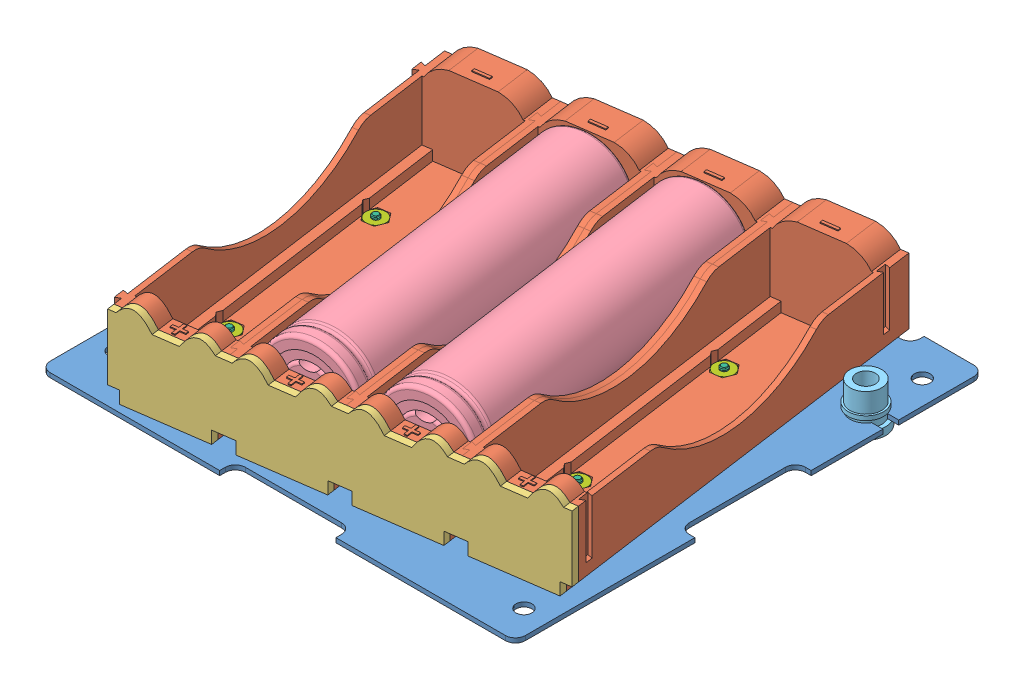
SolidWorks assembly M101 Battery Assembly, configuration Default. Lengths in mm.
Overall size (95.95 22.45 94.09).
43 component instances, 8 part files, 90 mates.
Components (placement in the parent):
- M103 Battery Plate-1: M103 Battery Plate [Default] at (-64.3857 -9.2767 40.2779) size (95.46 0.9 94.09)
- M102 Battery Holder Assembly-1: M102 Battery Holder Assembly [Default] at (-18.4887 8.3398 -10.8914) x (-0.990268 0 0.139173) z (-0.139173 0 -0.990268) size (83.6 18.9 79.5)
  - single battery holder-1: single battery holder [Default] at (-25.8788 -16.7165 25.0128) size (21.65 18.9 78)
  - single battery holder-2: single battery holder [Default] at (-5.2288 -16.7165 25.0128) size (21.65 18.9 78)
  - single battery holder-3: single battery holder [Default] at (15.4212 -16.7165 25.0128) size (21.65 18.9 78)
  - single battery holder-4: single battery holder [Default] at (36.0712 -16.7165 25.0128) size (21.65 18.9 78)
  - battery pack cap-1: battery pack cap [Default] at (36.0712 -16.7165 -52.9872) x (-1 0 0) z (0 0 -1) size (82.6 17.7 1.5)
- Battery, 18650_LGABC11865_3.7V-2: Battery, 18650_LGABC11865_3.7V [Default] at (-11.1122 2.4733 4.0244) x (-0.990268 0 0.139173) z (0 1 0) size (18.3 64.95 18.3)
- Battery, 18650_LGABC11865_3.7V-3: Battery, 18650_LGABC11865_3.7V [Default] at (-31.5612 2.4733 6.8983) x (-0.990268 0 0.139173) z (0 1 0) size (18.3 64.95 18.3)
- grommet, 1-8in ID, 5269T211-2: grommet, 1-8in ID, 5269T211 [Default] at (21.2068 -2.8902 -24.7221) x (0.837169 0 0.546944) z (0.546944 0 -0.837169) size (7.94 7.94 7.94)
- screw, pan head, 0-80, 1_8L, 316SS, 91400A030-9: screw, pan head, 0-80, 1_8L, 316SS, 91400A030 [91400A030] at (-49.1372 -6.1017 -8.9448) x (-0.837169 0 -0.546944) z (0 -1 0) size (2.95 2.95 4.29)
- screw, pan head, 0-80, 1_8L, 316SS, 91400A030-10: screw, pan head, 0-80, 1_8L, 316SS, 91400A030 [91400A030] at (-39.4821 -6.1017 -10.3017) x (-0.837169 0 -0.546944) z (0 -1 0) size (2.95 2.95 4.29)
- screw, pan head, 0-80, 1_8L, 316SS, 91400A030-11: screw, pan head, 0-80, 1_8L, 316SS, 91400A030 [91400A030] at (-59.9311 -6.1017 -7.4278) x (-0.837169 0 -0.546944) z (0 -1 0) size (2.95 2.95 4.29)
- screw, pan head, 0-80, 1_8L, 316SS, 91400A030-12: screw, pan head, 0-80, 1_8L, 316SS, 91400A030 [91400A030] at (-28.6882 -6.1017 -11.8187) x (-0.837169 0 -0.546944) z (0 -1 0) size (2.95 2.95 4.29)
- screw, pan head, 0-80, 1_8L, 316SS, 91400A030-13: screw, pan head, 0-80, 1_8L, 316SS, 91400A030 [91400A030] at (-55.1157 -6.1017 26.8355) x (-0.837169 0 -0.546944) z (0 -1 0) size (2.95 2.95 4.29)
- screw, pan head, 0-80, 1_8L, 316SS, 91400A030-14: screw, pan head, 0-80, 1_8L, 316SS, 91400A030 [91400A030] at (-44.3218 -6.1017 25.3185) x (-0.837169 0 -0.546944) z (0 -1 0) size (2.95 2.95 4.29)
- screw, pan head, 0-80, 1_8L, 316SS, 91400A030-15: screw, pan head, 0-80, 1_8L, 316SS, 91400A030 [91400A030] at (17.0253 -6.1017 16.6967) x (1 0 0) z (0 -1 0) size (2.95 2.95 4.29)
- screw, pan head, 0-80, 1_8L, 316SS, 91400A030-16: screw, pan head, 0-80, 1_8L, 316SS, 91400A030 [91400A030] at (-34.6667 -6.1017 23.9615) x (-0.837169 0 -0.546944) z (0 -1 0) size (2.95 2.95 4.29)
- screw, pan head, 0-80, 1_8L, 316SS, 91400A030-17: screw, pan head, 0-80, 1_8L, 316SS, 91400A030 [91400A030] at (12.2099 -6.1017 -17.5666) x (-0.837169 0 -0.546944) z (0 -1 0) size (2.95 2.95 4.29)
- screw, pan head, 0-80, 1_8L, 316SS, 91400A030-18: screw, pan head, 0-80, 1_8L, 316SS, 91400A030 [91400A030] at (-19.0331 -6.1017 -13.1757) x (-0.837169 0 -0.546944) z (0 -1 0) size (2.95 2.95 4.29)
- screw, pan head, 0-80, 1_8L, 316SS, 91400A030-19: screw, pan head, 0-80, 1_8L, 316SS, 91400A030 [91400A030] at (-8.2391 -6.1017 -14.6926) x (-0.837169 0 -0.546944) z (0 -1 0) size (2.95 2.95 4.29)
- screw, pan head, 0-80, 1_8L, 316SS, 91400A030-20: screw, pan head, 0-80, 1_8L, 316SS, 91400A030 [91400A030] at (1.416 -6.1017 -16.0496) x (-0.837169 0 -0.546944) z (0 -1 0) size (2.95 2.95 4.29)
- screw, pan head, 0-80, 1_8L, 316SS, 91400A030-21: screw, pan head, 0-80, 1_8L, 316SS, 91400A030 [91400A030] at (-23.8728 -6.1017 22.4446) x (-0.837169 0 -0.546944) z (0 -1 0) size (2.95 2.95 4.29)
- screw, pan head, 0-80, 1_8L, 316SS, 91400A030-22: screw, pan head, 0-80, 1_8L, 316SS, 91400A030 [91400A030] at (-14.2177 -6.1017 21.0876) x (-0.837169 0 -0.546944) z (0 -1 0) size (2.95 2.95 4.29)
- screw, pan head, 0-80, 1_8L, 316SS, 91400A030-23: screw, pan head, 0-80, 1_8L, 316SS, 91400A030 [91400A030] at (-3.4238 -6.1017 19.5706) x (-0.837169 0 -0.546944) z (0 -1 0) size (2.95 2.95 4.29)
- screw, pan head, 0-80, 1_8L, 316SS, 91400A030-24: screw, pan head, 0-80, 1_8L, 316SS, 91400A030 [91400A030] at (6.2314 -6.1017 18.2137) x (-0.837169 0 -0.546944) z (0 -1 0) size (2.95 2.95 4.29)
- nut, 0-80, standard, 18-8SS, 91841A115-1: nut, 0-80, standard, 18-8SS, 91841A115 [91841A115] at (1.4049 -7.9267 -16.0638) x (0.788011 0 -0.615661) z (0.615661 0 0.788011) size (3.97 1.19 5.04)
- nut, 0-80, standard, 18-8SS, 91841A115-2: nut, 0-80, standard, 18-8SS, 91841A115 [91841A115] at (-14.2177 -7.9267 21.0876) x (-0.990268 0 0.139173) z (-0.139173 0 -0.990268) size (3.97 1.19 5.04)
- nut, 0-80, standard, 18-8SS, 91841A115-3: nut, 0-80, standard, 18-8SS, 91841A115 [91841A115] at (-3.4238 -7.9267 19.5706) x (-0.990268 0 0.139173) z (-0.139173 0 -0.990268) size (3.97 1.19 5.04)
- nut, 0-80, standard, 18-8SS, 91841A115-4: nut, 0-80, standard, 18-8SS, 91841A115 [91841A115] at (-8.2391 -7.9267 -14.6926) x (-0.990268 0 0.139173) z (-0.139173 0 -0.990268) size (3.97 1.19 5.04)
- nut, 0-80, standard, 18-8SS, 91841A115-5: nut, 0-80, standard, 18-8SS, 91841A115 [91841A115] at (-19.0331 -7.9267 -13.1757) x (-0.990268 0 0.139173) z (-0.139173 0 -0.990268) size (3.97 1.19 5.04)
- nut, 0-80, standard, 18-8SS, 91841A115-6: nut, 0-80, standard, 18-8SS, 91841A115 [91841A115] at (-39.4821 -7.9267 -10.3017) x (-0.990268 0 0.139173) z (-0.139173 0 -0.990268) size (3.97 1.19 5.04)
- nut, 0-80, standard, 18-8SS, 91841A115-7: nut, 0-80, standard, 18-8SS, 91841A115 [91841A115] at (-28.6882 -7.9267 -11.8187) x (-0.990268 0 0.139173) z (-0.139173 0 -0.990268) size (3.97 1.19 5.04)
- nut, 0-80, standard, 18-8SS, 91841A115-8: nut, 0-80, standard, 18-8SS, 91841A115 [91841A115] at (-23.8728 -7.9267 22.4446) x (-0.990268 0 0.139173) z (-0.139173 0 -0.990268) size (3.97 1.19 5.04)
- nut, 0-80, standard, 18-8SS, 91841A115-9: nut, 0-80, standard, 18-8SS, 91841A115 [91841A115] at (-34.6667 -7.9267 23.9615) x (-0.990268 0 0.139173) z (-0.139173 0 -0.990268) size (3.97 1.19 5.04)
- nut, 0-80, standard, 18-8SS, 91841A115-10: nut, 0-80, standard, 18-8SS, 91841A115 [91841A115] at (-59.9311 -7.9267 -7.4278) x (-0.990268 0 0.139173) z (-0.139173 0 -0.990268) size (3.97 1.19 5.04)
- nut, 0-80, standard, 18-8SS, 91841A115-11: nut, 0-80, standard, 18-8SS, 91841A115 [91841A115] at (-49.1372 -7.9267 -8.9448) x (-0.990268 0 0.139173) z (-0.139173 0 -0.990268) size (3.97 1.19 5.04)
- nut, 0-80, standard, 18-8SS, 91841A115-12: nut, 0-80, standard, 18-8SS, 91841A115 [91841A115] at (-44.3218 -7.9267 25.3185) x (-0.990268 0 0.139173) z (-0.139173 0 -0.990268) size (3.97 1.19 5.04)
- nut, 0-80, standard, 18-8SS, 91841A115-13: nut, 0-80, standard, 18-8SS, 91841A115 [91841A115] at (-55.1157 -7.9267 26.8355) x (-0.990268 0 0.139173) z (-0.139173 0 -0.990268) size (3.97 1.19 5.04)
- nut, 0-80, standard, 18-8SS, 91841A115-14: nut, 0-80, standard, 18-8SS, 91841A115 [91841A115] at (6.2314 -7.9267 18.2137) x (-0.990268 0 0.139173) z (-0.139173 0 -0.990268) size (3.97 1.19 5.04)
- nut, 0-80, standard, 18-8SS, 91841A115-15: nut, 0-80, standard, 18-8SS, 91841A115 [91841A115] at (17.0253 -7.9267 16.6967) x (-0.990268 0 0.139173) z (-0.139173 0 -0.990268) size (3.97 1.19 5.04)
- nut, 0-80, standard, 18-8SS, 91841A115-16: nut, 0-80, standard, 18-8SS, 91841A115 [91841A115] at (12.2099 -7.9267 -17.5666) x (-0.990268 0 0.139173) z (-0.139173 0 -0.990268) size (3.97 1.19 5.04)
- SCOTCH WELD EC2216-1: SCOTCH WELD EC2216 [Default] at origin
Mates (geometry in assembly coordinates):
- Coincident1: coincident anti-aligned: plane of M103 Battery Plate-1 through (-69.2532 -8.3767 -36.7907) normal (0 1 0); plane of M102 Battery Holder Assembly-1/single battery holder-4 through (-60.2184 -8.3767 10.1078) normal (0 -1 0)
- Angle1: planar angle = 0.139626 rad anti-aligned: plane of assembly through (0 0 0) normal (1 0 0); plane of M102 Battery Holder Assembly-1 through (-18.4887 8.3398 -10.8914) normal (-0.990268 0 0.139173)
- Concentric4: concentric aligned: cylinder of M103 Battery Plate-1 through (21.2068 -9.2767 -24.7221) axis (0 1 0) radius 3.175; cylinder of grommet, 1-8in ID, 5269T211-2 through (21.2068 -2.8902 -24.7221) axis (0 1 0) radius 3.175
- Coincident3: coincident anti-aligned: plane of grommet, 1-8in ID, 5269T211-2 through (24.5293 -9.2767 -22.5514) normal (0 1 0); plane of M103 Battery Plate-1 through (-69.2532 -9.2767 -36.7907) normal (0 -1 0)
- Coincident4: coincident anti-aligned: plane of M103 Battery Plate-1 through (-69.2532 -9.2767 -36.7907) normal (0 -1 0); plane of screw, pan head, 0-80, 1_8L, 316SS, 91400A030-13 through (-55.1157 -9.2767 26.8355) normal (0 1 0)
- Coincident5: coincident anti-aligned: plane of M103 Battery Plate-1 through (-69.2532 -9.2767 -36.7907) normal (0 -1 0); plane of screw, pan head, 0-80, 1_8L, 316SS, 91400A030-16 through (-34.6667 -9.2767 23.9615) normal (0 1 0)
- Coincident6: coincident anti-aligned: plane of M103 Battery Plate-1 through (-69.2532 -9.2767 -36.7907) normal (0 -1 0); plane of screw, pan head, 0-80, 1_8L, 316SS, 91400A030-14 through (-44.3218 -9.2767 25.3185) normal (0 1 0)
- Coincident7: coincident anti-aligned: plane of M103 Battery Plate-1 through (-69.2532 -9.2767 -36.7907) normal (0 -1 0); plane of screw, pan head, 0-80, 1_8L, 316SS, 91400A030-23 through (-3.4238 -9.2767 19.5706) normal (0 1 0)
- Coincident8: coincident anti-aligned: plane of M103 Battery Plate-1 through (-69.2532 -9.2767 -36.7907) normal (0 -1 0); plane of screw, pan head, 0-80, 1_8L, 316SS, 91400A030-24 through (6.2314 -9.2767 18.2137) normal (0 1 0)
- Coincident9: coincident anti-aligned: plane of M103 Battery Plate-1 through (-69.2532 -9.2767 -36.7907) normal (0 -1 0); plane of screw, pan head, 0-80, 1_8L, 316SS, 91400A030-22 through (-14.2177 -9.2767 21.0876) normal (0 1 0)
- Coincident10: coincident anti-aligned: plane of M103 Battery Plate-1 through (-69.2532 -9.2767 -36.7907) normal (0 -1 0); plane of screw, pan head, 0-80, 1_8L, 316SS, 91400A030-11 through (-59.9311 -9.2767 -7.4278) normal (0 1 0)
- Coincident11: coincident anti-aligned: plane of M103 Battery Plate-1 through (-69.2532 -9.2767 -36.7907) normal (0 -1 0); plane of screw, pan head, 0-80, 1_8L, 316SS, 91400A030-21 through (-23.8728 -9.2767 22.4446) normal (0 1 0)
- Coincident12: coincident anti-aligned: plane of M103 Battery Plate-1 through (-69.2532 -9.2767 -36.7907) normal (0 -1 0); plane of screw, pan head, 0-80, 1_8L, 316SS, 91400A030-12 through (-28.6882 -9.2767 -11.8187) normal (0 1 0)
- Coincident13: coincident anti-aligned: plane of M103 Battery Plate-1 through (-69.2532 -9.2767 -36.7907) normal (0 -1 0); plane of screw, pan head, 0-80, 1_8L, 316SS, 91400A030-9 through (-49.1372 -9.2767 -8.9448) normal (0 1 0)
- Coincident14: coincident anti-aligned: plane of M103 Battery Plate-1 through (-69.2532 -9.2767 -36.7907) normal (0 -1 0); plane of screw, pan head, 0-80, 1_8L, 316SS, 91400A030-10 through (-39.4821 -9.2767 -10.3017) normal (0 1 0)
- Coincident15: coincident anti-aligned: plane of M103 Battery Plate-1 through (-69.2532 -9.2767 -36.7907) normal (0 -1 0); plane of screw, pan head, 0-80, 1_8L, 316SS, 91400A030-18 through (-19.0331 -9.2767 -13.1757) normal (0 1 0)
- Coincident16: coincident anti-aligned: plane of M103 Battery Plate-1 through (-69.2532 -9.2767 -36.7907) normal (0 -1 0); plane of screw, pan head, 0-80, 1_8L, 316SS, 91400A030-19 through (-8.2391 -9.2767 -14.6926) normal (0 1 0)
- Coincident17: coincident anti-aligned: plane of M103 Battery Plate-1 through (-69.2532 -9.2767 -36.7907) normal (0 -1 0); plane of screw, pan head, 0-80, 1_8L, 316SS, 91400A030-20 through (1.416 -9.2767 -16.0496) normal (0 1 0)
- Coincident18: coincident anti-aligned: plane of M103 Battery Plate-1 through (-69.2532 -9.2767 -36.7907) normal (0 -1 0); plane of screw, pan head, 0-80, 1_8L, 316SS, 91400A030-17 through (12.2099 -9.2767 -17.5666) normal (0 1 0)
- Coincident20: coincident anti-aligned: plane of M103 Battery Plate-1 through (-69.2532 -9.2767 -36.7907) normal (0 -1 0); plane of screw, pan head, 0-80, 1_8L, 316SS, 91400A030-15 through (17.0253 -9.2767 16.6967) normal (0 1 0)
- Concentric5: concentric anti-aligned: circle of M103 Battery Plate-1; circle of screw, pan head, 0-80, 1_8L, 316SS, 91400A030-17
- Concentric6: concentric anti-aligned: circle of screw, pan head, 0-80, 1_8L, 316SS, 91400A030-20; circle of M103 Battery Plate-1
- Concentric7: concentric anti-aligned: circle of M103 Battery Plate-1; circle of screw, pan head, 0-80, 1_8L, 316SS, 91400A030-19
- Concentric8: concentric anti-aligned: circle of M103 Battery Plate-1; circle of screw, pan head, 0-80, 1_8L, 316SS, 91400A030-18
- Concentric9: concentric anti-aligned: circle of M103 Battery Plate-1; circle of screw, pan head, 0-80, 1_8L, 316SS, 91400A030-12
- Concentric10: concentric anti-aligned: circle of M103 Battery Plate-1; circle of screw, pan head, 0-80, 1_8L, 316SS, 91400A030-10
- Concentric11: concentric anti-aligned: circle of M103 Battery Plate-1; circle of screw, pan head, 0-80, 1_8L, 316SS, 91400A030-9
- Concentric12: concentric anti-aligned: circle of M103 Battery Plate-1; circle of screw, pan head, 0-80, 1_8L, 316SS, 91400A030-11
- Concentric13: concentric anti-aligned: circle of M103 Battery Plate-1; circle of screw, pan head, 0-80, 1_8L, 316SS, 91400A030-24
- Concentric14: concentric anti-aligned: circle of M103 Battery Plate-1; circle of screw, pan head, 0-80, 1_8L, 316SS, 91400A030-23
- Concentric15: concentric anti-aligned: circle of M103 Battery Plate-1; circle of screw, pan head, 0-80, 1_8L, 316SS, 91400A030-22
- Concentric16: concentric anti-aligned: circle of M103 Battery Plate-1; circle of screw, pan head, 0-80, 1_8L, 316SS, 91400A030-21
- Concentric17: concentric anti-aligned: circle of M103 Battery Plate-1; circle of screw, pan head, 0-80, 1_8L, 316SS, 91400A030-16
- Concentric18: concentric anti-aligned: circle of M103 Battery Plate-1; circle of screw, pan head, 0-80, 1_8L, 316SS, 91400A030-14
- Concentric19: concentric anti-aligned: circle of M103 Battery Plate-1; circle of screw, pan head, 0-80, 1_8L, 316SS, 91400A030-13
- Concentric20: concentric anti-aligned: circle of M103 Battery Plate-1; circle of screw, pan head, 0-80, 1_8L, 316SS, 91400A030-15
- Coincident22: coincident aligned: plane of M102 Battery Holder Assembly-1/single battery holder-2 through (-16.7919 -8.3767 -36.3885) normal (-0.990268 0 0.139173); plane of Battery, 18650_LGABC11865_3.7V-2 through (-11.1122 2.4733 4.0244) normal (-0.990268 0 0.139173)
- Tangent2: tangent anti-aligned: plane of M102 Battery Holder Assembly-1/single battery holder-2 through (-16.7919 11.6233 -36.3885) normal (0 -1 0); cylinder of Battery, 18650_LGABC11865_3.7V-2 through (-6.596 2.4733 36.1586) axis (-0.139173 0 -0.990268) radius 9.15
- Coincident23: coincident aligned: plane of Battery, 18650_LGABC11865_3.7V-2 through (-15.6284 2.4733 -28.1098) normal (-0.139173 0 -0.990268); plane of Battery, 18650_LGABC11865_3.7V-3 through (-36.0774 2.4733 -25.2359) normal (-0.139173 0 -0.990268)
- Coincident24: coincident aligned: plane of M102 Battery Holder Assembly-1/single battery holder-3 through (-37.2409 -8.3767 -33.5146) normal (-0.990268 0 0.139173); plane of Battery, 18650_LGABC11865_3.7V-3 through (-31.5612 2.4733 6.8983) normal (-0.990268 0 0.139173)
- Tangent3: tangent anti-aligned: plane of M102 Battery Holder Assembly-1/single battery holder-3 through (-37.2409 11.6233 -33.5146) normal (0 -1 0); cylinder of Battery, 18650_LGABC11865_3.7V-3 through (-27.0451 2.4733 39.0325) axis (-0.139173 0 -0.990268) radius 9.15
- Concentric21: concentric aligned: cylinder of M103 Battery Plate-1 through (12.2099 -8.3767 -17.5666) axis (0 -1 0) radius 0.925; cylinder of M102 Battery Holder Assembly-1/single battery holder-1 through (12.2099 10.3234 -17.5666) axis (0 -1 0) radius 0.925
- Coincident27: coincident anti-aligned: plane of nut, 0-80, standard, 18-8SS, 91841A115-1 through (-0.0058 -7.9267 -17.8694) normal (0 -1 0); plane of M102 Battery Holder Assembly-1/single battery holder-1 through (3.7029 -7.9267 -16.371) normal (0 1 0)
- Coincident28: coincident anti-aligned: plane of nut, 0-80, standard, 18-8SS, 91841A115-1 through (2.2632 -6.736 -18.1883) normal (-0.139173 0 -0.990268); plane of M102 Battery Holder Assembly-1/single battery holder-1 through (2.2811 10.3234 -18.1908) normal (0.139173 0 0.990268)
- Coincident29: coincident anti-aligned: plane of nut, 0-80, standard, 18-8SS, 91841A115-1 through (-0.0058 -6.736 -17.8694) normal (-0.927184 0 -0.374607); plane of M102 Battery Holder Assembly-1/single battery holder-1 through (-0.0058 10.3234 -17.8694) normal (0.927184 0 0.374607)
- Coincident33: coincident aligned: plane of nut, 0-80, standard, 18-8SS, 91841A115-16 through (12.5288 -7.9267 -15.2975) normal (0 -1 0); plane of nut, 0-80, standard, 18-8SS, 91841A115-2 through (-13.8988 -7.9267 23.3567) normal (0 -1 0)
- Parallel15: parallel aligned: plane of M102 Battery Holder Assembly-1 through (-18.4887 8.3398 -10.8914) normal (-0.139173 0 -0.990268); plane of nut, 0-80, standard, 18-8SS, 91841A115-2 through (-14.2177 -7.9267 21.0876) normal (-0.139173 0 -0.990268)
- Concentric22: concentric aligned: circle of M102 Battery Holder Assembly-1/single battery holder-2; circle of nut, 0-80, standard, 18-8SS, 91841A115-2
- Coincident31: coincident aligned: plane of nut, 0-80, standard, 18-8SS, 91841A115-16 through (12.5288 -7.9267 -15.2975) normal (0 -1 0); plane of nut, 0-80, standard, 18-8SS, 91841A115-3 through (-3.1049 -7.9267 21.8397) normal (0 -1 0)
- Parallel1: parallel aligned: plane of M102 Battery Holder Assembly-1 through (-18.4887 8.3398 -10.8914) normal (-0.139173 0 -0.990268); plane of nut, 0-80, standard, 18-8SS, 91841A115-3 through (-3.4238 -7.9267 19.5706) normal (-0.139173 0 -0.990268)
- Concentric23: concentric aligned: circle of M102 Battery Holder Assembly-1/single battery holder-2; circle of nut, 0-80, standard, 18-8SS, 91841A115-3
- Coincident32: coincident aligned: plane of nut, 0-80, standard, 18-8SS, 91841A115-16 through (12.5288 -7.9267 -15.2975) normal (0 -1 0); plane of nut, 0-80, standard, 18-8SS, 91841A115-4 through (-7.9202 -7.9267 -12.4236) normal (0 -1 0)
- Parallel2: parallel aligned: plane of M102 Battery Holder Assembly-1 through (-18.4887 8.3398 -10.8914) normal (-0.139173 0 -0.990268); plane of nut, 0-80, standard, 18-8SS, 91841A115-4 through (-8.2391 -7.9267 -14.6926) normal (-0.139173 0 -0.990268)
- Concentric24: concentric aligned: circle of M102 Battery Holder Assembly-1/single battery holder-2; circle of nut, 0-80, standard, 18-8SS, 91841A115-4
- Coincident34: coincident aligned: plane of nut, 0-80, standard, 18-8SS, 91841A115-16 through (12.5288 -7.9267 -15.2975) normal (0 -1 0); plane of nut, 0-80, standard, 18-8SS, 91841A115-5 through (-18.7142 -7.9267 -10.9066) normal (0 -1 0)
- Parallel3: parallel aligned: plane of M102 Battery Holder Assembly-1 through (-18.4887 8.3398 -10.8914) normal (-0.139173 0 -0.990268); plane of nut, 0-80, standard, 18-8SS, 91841A115-5 through (-19.0331 -7.9267 -13.1757) normal (-0.139173 0 -0.990268)
- Concentric25: concentric aligned: circle of M102 Battery Holder Assembly-1/single battery holder-2; circle of nut, 0-80, standard, 18-8SS, 91841A115-5
- Coincident37: coincident aligned: plane of nut, 0-80, standard, 18-8SS, 91841A115-16 through (12.5288 -7.9267 -15.2975) normal (0 -1 0); plane of nut, 0-80, standard, 18-8SS, 91841A115-6 through (-39.1632 -7.9267 -8.0327) normal (0 -1 0)
- Parallel4: parallel aligned: plane of M102 Battery Holder Assembly-1 through (-18.4887 8.3398 -10.8914) normal (-0.139173 0 -0.990268); plane of nut, 0-80, standard, 18-8SS, 91841A115-6 through (-39.4821 -7.9267 -10.3017) normal (-0.139173 0 -0.990268)
- Concentric26: concentric aligned: circle of M102 Battery Holder Assembly-1/single battery holder-3; circle of nut, 0-80, standard, 18-8SS, 91841A115-6
- Coincident36: coincident aligned: plane of nut, 0-80, standard, 18-8SS, 91841A115-16 through (12.5288 -7.9267 -15.2975) normal (0 -1 0); plane of nut, 0-80, standard, 18-8SS, 91841A115-7 through (-28.3693 -7.9267 -9.5497) normal (0 -1 0)
- Parallel5: parallel aligned: plane of M102 Battery Holder Assembly-1 through (-18.4887 8.3398 -10.8914) normal (-0.139173 0 -0.990268); plane of nut, 0-80, standard, 18-8SS, 91841A115-7 through (-28.6882 -7.9267 -11.8187) normal (-0.139173 0 -0.990268)
- Concentric27: concentric aligned: circle of M102 Battery Holder Assembly-1/single battery holder-3; circle of nut, 0-80, standard, 18-8SS, 91841A115-7
- Coincident35: coincident aligned: plane of nut, 0-80, standard, 18-8SS, 91841A115-16 through (12.5288 -7.9267 -15.2975) normal (0 -1 0); plane of nut, 0-80, standard, 18-8SS, 91841A115-8 through (-23.5539 -7.9267 24.7136) normal (0 -1 0)
- Parallel6: parallel aligned: plane of M102 Battery Holder Assembly-1 through (-18.4887 8.3398 -10.8914) normal (-0.139173 0 -0.990268); plane of nut, 0-80, standard, 18-8SS, 91841A115-8 through (-23.8728 -7.9267 22.4446) normal (-0.139173 0 -0.990268)
- Concentric28: concentric aligned: circle of M102 Battery Holder Assembly-1/single battery holder-3; circle of nut, 0-80, standard, 18-8SS, 91841A115-8
- Coincident38: coincident aligned: plane of nut, 0-80, standard, 18-8SS, 91841A115-16 through (12.5288 -7.9267 -15.2975) normal (0 -1 0); plane of nut, 0-80, standard, 18-8SS, 91841A115-9 through (-34.3478 -7.9267 26.2306) normal (0 -1 0)
- Parallel7: parallel aligned: plane of M102 Battery Holder Assembly-1 through (-18.4887 8.3398 -10.8914) normal (-0.139173 0 -0.990268); plane of nut, 0-80, standard, 18-8SS, 91841A115-9 through (-34.6667 -7.9267 23.9615) normal (-0.139173 0 -0.990268)
- Concentric29: concentric aligned: circle of M102 Battery Holder Assembly-1/single battery holder-3; circle of nut, 0-80, standard, 18-8SS, 91841A115-9
- Coincident42: coincident aligned: plane of nut, 0-80, standard, 18-8SS, 91841A115-16 through (12.5288 -7.9267 -15.2975) normal (0 -1 0); plane of nut, 0-80, standard, 18-8SS, 91841A115-10 through (-59.6122 -7.9267 -5.1588) normal (0 -1 0)
- Parallel8: parallel aligned: plane of M102 Battery Holder Assembly-1 through (-18.4887 8.3398 -10.8914) normal (-0.139173 0 -0.990268); plane of nut, 0-80, standard, 18-8SS, 91841A115-10 through (-59.9311 -7.9267 -7.4278) normal (-0.139173 0 -0.990268)
- Concentric30: concentric aligned: circle of M102 Battery Holder Assembly-1/single battery holder-4; circle of nut, 0-80, standard, 18-8SS, 91841A115-10
- Coincident39: coincident aligned: plane of nut, 0-80, standard, 18-8SS, 91841A115-16 through (12.5288 -7.9267 -15.2975) normal (0 -1 0); plane of nut, 0-80, standard, 18-8SS, 91841A115-11 through (-48.8183 -7.9267 -6.6757) normal (0 -1 0)
- Parallel14: parallel aligned: plane of M102 Battery Holder Assembly-1 through (-18.4887 8.3398 -10.8914) normal (-0.139173 0 -0.990268); plane of nut, 0-80, standard, 18-8SS, 91841A115-11 through (-49.1372 -7.9267 -8.9448) normal (-0.139173 0 -0.990268)
- Concentric31: concentric aligned: circle of M102 Battery Holder Assembly-1/single battery holder-4; circle of nut, 0-80, standard, 18-8SS, 91841A115-11
- Coincident40: coincident aligned: plane of nut, 0-80, standard, 18-8SS, 91841A115-16 through (12.5288 -7.9267 -15.2975) normal (0 -1 0); plane of nut, 0-80, standard, 18-8SS, 91841A115-12 through (-44.0029 -7.9267 27.5875) normal (0 -1 0)
- Parallel9: parallel aligned: plane of M102 Battery Holder Assembly-1 through (-18.4887 8.3398 -10.8914) normal (-0.139173 0 -0.990268); plane of nut, 0-80, standard, 18-8SS, 91841A115-12 through (-44.3218 -7.9267 25.3185) normal (-0.139173 0 -0.990268)
- Concentric32: concentric aligned: circle of M102 Battery Holder Assembly-1/single battery holder-4; circle of nut, 0-80, standard, 18-8SS, 91841A115-12
- Coincident41: coincident aligned: plane of nut, 0-80, standard, 18-8SS, 91841A115-16 through (12.5288 -7.9267 -15.2975) normal (0 -1 0); plane of nut, 0-80, standard, 18-8SS, 91841A115-13 through (-54.7969 -7.9267 29.1045) normal (0 -1 0)
- Parallel10: parallel aligned: plane of M102 Battery Holder Assembly-1 through (-18.4887 8.3398 -10.8914) normal (-0.139173 0 -0.990268); plane of nut, 0-80, standard, 18-8SS, 91841A115-13 through (-55.1157 -7.9267 26.8355) normal (-0.139173 0 -0.990268)
- Concentric33: concentric aligned: circle of M102 Battery Holder Assembly-1/single battery holder-4; circle of nut, 0-80, standard, 18-8SS, 91841A115-13
- Coincident30: coincident aligned: plane of nut, 0-80, standard, 18-8SS, 91841A115-16 through (12.5288 -7.9267 -15.2975) normal (0 -1 0); plane of nut, 0-80, standard, 18-8SS, 91841A115-14 through (6.5503 -7.9267 20.4828) normal (0 -1 0)
- Parallel11: parallel aligned: plane of M102 Battery Holder Assembly-1 through (-18.4887 8.3398 -10.8914) normal (-0.139173 0 -0.990268); plane of nut, 0-80, standard, 18-8SS, 91841A115-14 through (6.2314 -7.9267 18.2137) normal (-0.139173 0 -0.990268)
- Concentric34: concentric aligned: circle of M102 Battery Holder Assembly-1/single battery holder-1; circle of nut, 0-80, standard, 18-8SS, 91841A115-14
- Coincident43: coincident aligned: plane of nut, 0-80, standard, 18-8SS, 91841A115-16 through (12.5288 -7.9267 -15.2975) normal (0 -1 0); plane of nut, 0-80, standard, 18-8SS, 91841A115-15 through (17.3442 -7.9267 18.9658) normal (0 -1 0)
- Parallel12: parallel aligned: plane of M102 Battery Holder Assembly-1 through (-18.4887 8.3398 -10.8914) normal (-0.139173 0 -0.990268); plane of nut, 0-80, standard, 18-8SS, 91841A115-15 through (17.0253 -7.9267 16.6967) normal (-0.139173 0 -0.990268)
- Concentric35: concentric aligned: circle of M102 Battery Holder Assembly-1/single battery holder-1; circle of nut, 0-80, standard, 18-8SS, 91841A115-15
- Coincident44: coincident anti-aligned: plane of nut, 0-80, standard, 18-8SS, 91841A115-16 through (12.5288 -7.9267 -15.2975) normal (0 -1 0); plane of M102 Battery Holder Assembly-1/single battery holder-1 through (9.923 -7.9267 -17.2452) normal (0 1 0)
- Parallel13: parallel aligned: plane of M102 Battery Holder Assembly-1 through (-18.4887 8.3398 -10.8914) normal (-0.139173 0 -0.990268); plane of nut, 0-80, standard, 18-8SS, 91841A115-16 through (12.2099 -7.9267 -17.5666) normal (-0.139173 0 -0.990268)
- Concentric36: concentric aligned: circle of M102 Battery Holder Assembly-1/single battery holder-1; circle of nut, 0-80, standard, 18-8SS, 91841A115-16
